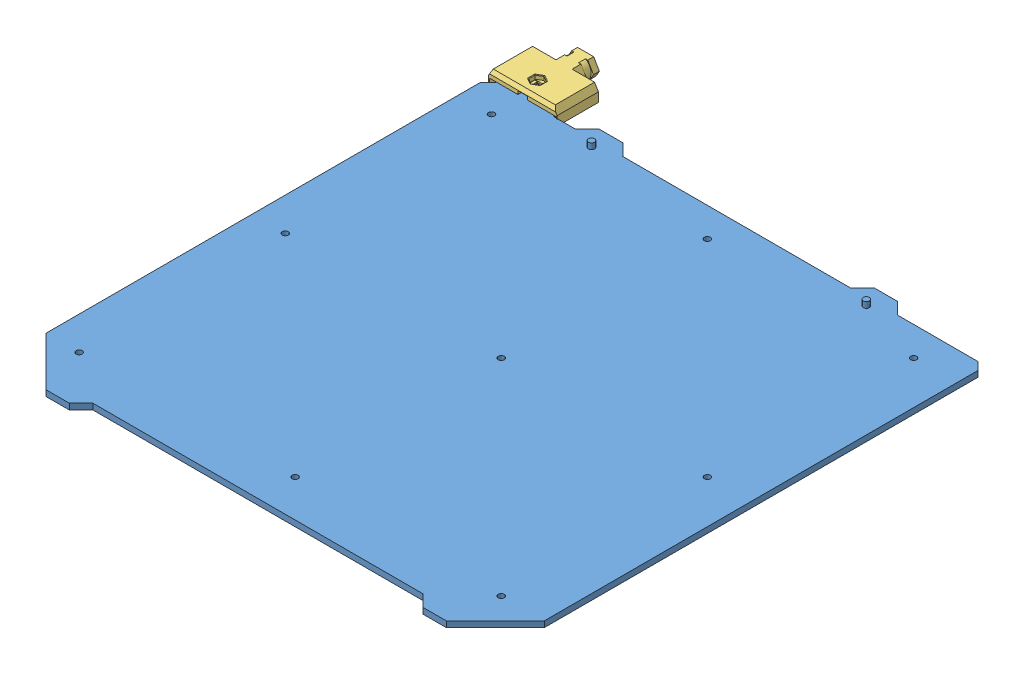
SolidWorks assembly Headbed Assembly, configuration Default. Lengths in mm.
Overall size (253.8 14 281.4).
11 component instances, 3 part files, 21 mates.
Components (placement in the parent):
- MK52 Bed-1: MK52 Bed [Default] at (-64.502 153.1745 327.7347) size (253.8 6 264.25)
- 6x6x3t spacer-1: 6x6x3t spacer [Default] at (62.498 147.1745 212.6933) size (6 6 6)
- 6x6x3t spacer-2: 6x6x3t spacer [Default] at (62.498 147.1745 107.6933) size (6 6 6)
- 6x6x3t spacer-3: 6x6x3t spacer [Default] at (-47.502 147.1745 317.6933) size (6 6 6)
- 6x6x3t spacer-4: 6x6x3t spacer [Default] at (-47.502 147.1745 107.6933) x (0.97497 0 -0.222336) z (0.222336 0 0.97497) size (6 6 6)
- 6x6x3t spacer-5: 6x6x3t spacer [Default] at (167.498 147.1745 317.6933) size (6 6 6)
- 6x6x3t spacer-6: 6x6x3t spacer [Default] at (167.498 147.1745 212.6933) size (6 6 6)
- 6x6x3t spacer-7: 6x6x3t spacer [Default] at (167.498 147.1745 107.6933) x (0.999855 0 0.017002) z (-0.017002 0 0.999855) size (6 6 6)
- 6x6x3t spacer-8: 6x6x3t spacer [Default] at (62.498 147.1745 317.6933) size (6 6 6)
- 6x6x3t spacer-9: 6x6x3t spacer [Default] at (-47.502 147.1745 212.6933) size (6 6 6)
- heatbed-cable-cover-1: heatbed-cable-cover [Default] at (-46.0021 153.1745 93.2347) x (1 0 0) z (0 1 0) size (35 32 8)
Mates (geometry in assembly coordinates):
- Concentric1: concentric anti-aligned: circle of MK52 Bed-1; cylinder of 6x6x3t spacer-3 through (-47.502 153.1745 317.6933) axis (0 -1 0) radius 1.75
- Concentric2: concentric anti-aligned: circle of MK52 Bed-1; cylinder of 6x6x3t spacer-8 through (62.498 153.1745 317.6933) axis (0 -1 0) radius 1.75
- Concentric3: concentric anti-aligned: cylinder of MK52 Bed-1 through (167.498 153.1745 317.6933) axis (0 1 0) radius 1.55; cylinder of 6x6x3t spacer-5 through (167.498 153.1745 317.6933) axis (0 -1 0) radius 1.75
- Concentric4: concentric anti-aligned: circle of MK52 Bed-1; circle of 6x6x3t spacer-9
- Concentric5: concentric anti-aligned: circle of MK52 Bed-1; circle of 6x6x3t spacer-1
- Concentric6: concentric aligned: circle of MK52 Bed-1; circle of 6x6x3t spacer-6
- Concentric7: concentric anti-aligned: circle of MK52 Bed-1; circle of 6x6x3t spacer-4
- Concentric8: concentric anti-aligned: circle of MK52 Bed-1; circle of 6x6x3t spacer-2
- Concentric9: concentric aligned: circle of MK52 Bed-1; circle of 6x6x3t spacer-7
- Coincident1: coincident anti-aligned: plane of MK52 Bed-1 through (-64.502 153.1745 327.7347) normal (0 -1 0); plane of 6x6x3t spacer-8 through (62.498 153.1745 317.6933) normal (0 1 0)
- Coincident2: coincident anti-aligned: plane of MK52 Bed-1 through (-64.502 153.1745 327.7347) normal (0 -1 0); plane of 6x6x3t spacer-5 through (167.498 153.1745 317.6933) normal (0 1 0)
- Coincident3: coincident anti-aligned: plane of MK52 Bed-1 through (-64.502 153.1745 327.7347) normal (0 -1 0); plane of 6x6x3t spacer-3 through (-47.502 153.1745 317.6933) normal (0 1 0)
- Coincident4: coincident anti-aligned: plane of MK52 Bed-1 through (-64.502 153.1745 327.7347) normal (0 -1 0); plane of 6x6x3t spacer-9 through (-47.502 153.1745 212.6933) normal (0 1 0)
- Coincident5: coincident anti-aligned: plane of MK52 Bed-1 through (-64.502 153.1745 327.7347) normal (0 -1 0); plane of 6x6x3t spacer-1 through (62.498 153.1745 212.6933) normal (0 1 0)
- Coincident6: coincident anti-aligned: plane of MK52 Bed-1 through (-64.502 153.1745 327.7347) normal (0 -1 0); plane of 6x6x3t spacer-2 through (62.498 153.1745 107.6933) normal (0 1 0)
- Coincident7: coincident anti-aligned: plane of MK52 Bed-1 through (-64.502 153.1745 327.7347) normal (0 -1 0); plane of 6x6x3t spacer-6 through (167.498 153.1745 212.6933) normal (0 1 0)
- Coincident8: coincident anti-aligned: plane of MK52 Bed-1 through (-64.502 153.1745 327.7347) normal (0 -1 0); plane of 6x6x3t spacer-4 through (-47.502 153.1745 107.6933) normal (0 1 0)
- Coincident9: coincident anti-aligned: plane of MK52 Bed-1 through (-64.502 153.1745 327.7347) normal (0 -1 0); plane of 6x6x3t spacer-7 through (167.498 153.1745 107.6933) normal (0 1 0)
- Concentric10: concentric: circle of MK52 Bed-1; circle of heatbed-cable-cover-1
- Coincident11: coincident: plane of MK52 Bed-1 through (-64.502 153.1745 327.7347) normal (0 -1 0); plane of heatbed-cable-cover-1 through (-60.0021 153.1745 83.2347) normal (0 -1 0)
- Parallel1: parallel aligned: plane of MK52 Bed-1 through (-64.402 156.1745 327.7347) normal (-1 0 0); plane of heatbed-cable-cover-1 through (-63.5021 153.1745 93.2347) normal (-1 0 0)
